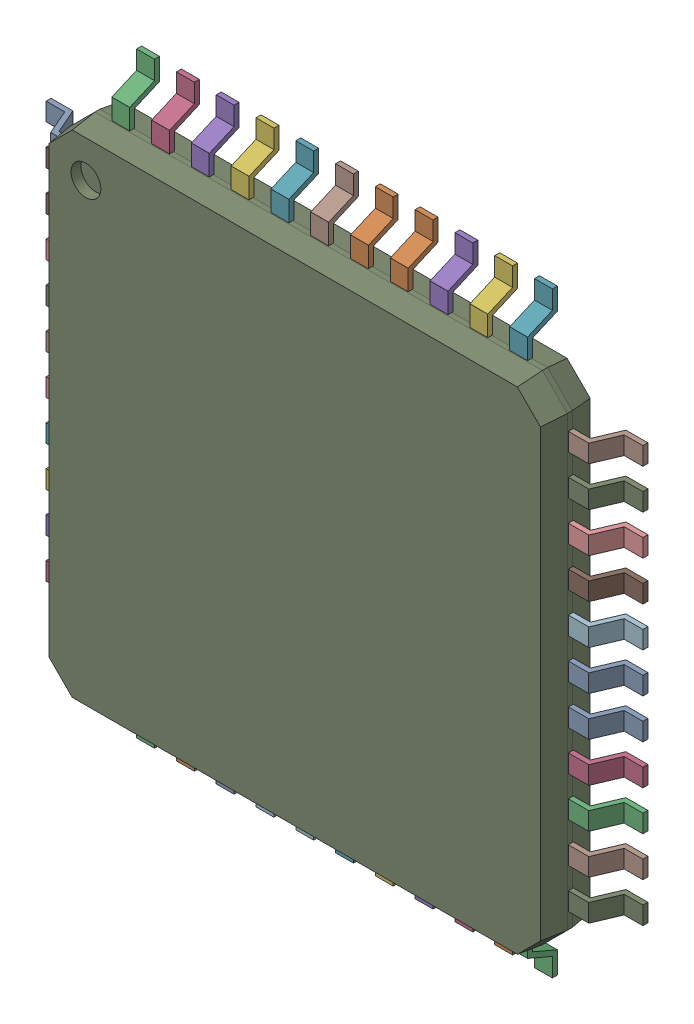
SolidWorks assembly DD2, configuration По умолчанию. Lengths in mm.
Overall size (12 12 1.1).
46 component instances, 45 part files, 0 mates.
Components (placement in the parent):
- User_Library-TQFP-44-1-1: User_Library-TQFP-44-1 [По умолчанию] at (28.4999 0.7811 0) x (0 -1 0) z (0 0 1) size (12 12 1.1)
  - User_Library-TQFP-44-1_pin001-1: User_Library-TQFP-44-1_pin001 [По умолчанию] at origin size (0.36 1 0.6)
  - User_Library-TQFP-44-1_pin021-1: User_Library-TQFP-44-1_pin021 [По умолчанию] at origin size (1 0.36 0.6)
  - User_Library-TQFP-44-1_pin022-1: User_Library-TQFP-44-1_pin022 [По умолчанию] at origin size (1 0.36 0.6)
  - User_Library-TQFP-44-1_pin020-1: User_Library-TQFP-44-1_pin020 [По умолчанию] at origin size (1 0.36 0.6)
  - User_Library-TQFP-44-1_pin019-1: User_Library-TQFP-44-1_pin019 [По умолчанию] at origin size (1 0.36 0.6)
  - User_Library-TQFP-44-1_pin018-1: User_Library-TQFP-44-1_pin018 [По умолчанию] at origin size (1 0.36 0.6)
  - User_Library-TQFP-44-1_pin017-1: User_Library-TQFP-44-1_pin017 [По умолчанию] at origin size (1 0.36 0.6)
  - User_Library-TQFP-44-1_pin024-1: User_Library-TQFP-44-1_pin024 [По умолчанию] at origin size (0.36 1 0.6)
  - User_Library-TQFP-44-1_pin023-1: User_Library-TQFP-44-1_pin023 [По умолчанию] at origin size (0.36 1 0.6)
  - User_Library-TQFP-44-1_pin007-1: User_Library-TQFP-44-1_pin007 [По умолчанию] at origin size (0.36 1 0.6)
  - User_Library-TQFP-44-1_pin003-1: User_Library-TQFP-44-1_pin003 [По умолчанию] at origin size (0.36 1 0.6)
  - User_Library-TQFP-44-1_pin015-1: User_Library-TQFP-44-1_pin015 [По умолчанию] at origin size (1 0.36 0.6)
  - User_Library-TQFP-44-1_pin014-1: User_Library-TQFP-44-1_pin014 [По умолчанию] at origin size (1 0.36 0.6)
  - User_Library-TQFP-44-1_pin013-1: User_Library-TQFP-44-1_pin013 [По умолчанию] at origin size (1 0.36 0.6)
  - User_Library-TQFP-44-1_pin012-1: User_Library-TQFP-44-1_pin012 [По умолчанию] at origin size (1 0.36 0.6)
  - User_Library-TQFP-44-1_pin011-1: User_Library-TQFP-44-1_pin011 [По умолчанию] at origin size (0.36 1 0.6)
  - User_Library-TQFP-44-1_pin010-1: User_Library-TQFP-44-1_pin010 [По умолчанию] at origin size (0.36 1 0.6)
  - User_Library-TQFP-44-1_pin009-1: User_Library-TQFP-44-1_pin009 [По умолчанию] at origin size (0.36 1 0.6)
  - User_Library-TQFP-44-1_pin008-1: User_Library-TQFP-44-1_pin008 [По умолчанию] at origin size (0.36 1 0.6)
  - User_Library-TQFP-44-1_pin006-1: User_Library-TQFP-44-1_pin006 [По умолчанию] at origin size (0.36 1 0.6)
  - User_Library-TQFP-44-1_pin005-1: User_Library-TQFP-44-1_pin005 [По умолчанию] at origin size (0.36 1 0.6)
  - User_Library-TQFP-44-1_pin004-1: User_Library-TQFP-44-1_pin004 [По умолчанию] at origin size (0.36 1 0.6)
  - User_Library-TQFP-44-1_pin002-1: User_Library-TQFP-44-1_pin002 [По умолчанию] at origin size (0.36 1 0.6)
  - User_Library-TQFP-44-1_pin016-1: User_Library-TQFP-44-1_pin016 [По умолчанию] at origin size (1 0.36 0.6)
  - User_Library-TQFP-44-1_pin027-1: User_Library-TQFP-44-1_pin027 [По умолчанию] at origin size (0.36 1 0.6)
  - User_Library-TQFP-44-1_pin037-1: User_Library-TQFP-44-1_pin037 [По умолчанию] at origin size (1 0.36 0.6)
  - User_Library-TQFP-44-1_pin025-1: User_Library-TQFP-44-1_pin025 [По умолчанию] at origin size (0.36 1 0.6)
  - User_Library-TQFP-44-1_pin026-1: User_Library-TQFP-44-1_pin026 [По умолчанию] at origin size (0.36 1 0.6)
  - User_Library-TQFP-44-1_pin036-1: User_Library-TQFP-44-1_pin036 [По умолчанию] at origin size (1 0.36 0.6)
  - User_Library-TQFP-44-1_pin035-1: User_Library-TQFP-44-1_pin035 [По умолчанию] at origin size (1 0.36 0.6)
  - User_Library-TQFP-44-1_pin034-1: User_Library-TQFP-44-1_pin034 [По умолчанию] at origin size (1 0.36 0.6)
  - User_Library-TQFP-44-1_pin033-1: User_Library-TQFP-44-1_pin033 [По умолчанию] at origin size (0.36 1 0.6)
  - User_Library-TQFP-44-1_pin032-1: User_Library-TQFP-44-1_pin032 [По умолчанию] at origin size (0.36 1 0.6)
  - User_Library-TQFP-44-1_pin031-1: User_Library-TQFP-44-1_pin031 [По умолчанию] at origin size (0.36 1 0.6)
  - User_Library-TQFP-44-1_pin030-1: User_Library-TQFP-44-1_pin030 [По умолчанию] at origin size (0.36 1 0.6)
  - User_Library-TQFP-44-1_pin029-1: User_Library-TQFP-44-1_pin029 [По умолчанию] at origin size (0.36 1 0.6)
  - User_Library-TQFP-44-1_pin028-1: User_Library-TQFP-44-1_pin028 [По умолчанию] at origin size (0.36 1 0.6)
  - User_Library-TQFP-44-1_pin038-1: User_Library-TQFP-44-1_pin038 [По умолчанию] at origin size (1 0.36 0.6)
  - User_Library-TQFP-44-1_pin044-1: User_Library-TQFP-44-1_pin044 [По умолчанию] at origin size (1 0.36 0.6)
  - User_Library-TQFP-44-1_pin043-1: User_Library-TQFP-44-1_pin043 [По умолчанию] at origin size (1 0.36 0.6)
  - User_Library-TQFP-44-1_pin042-1: User_Library-TQFP-44-1_pin042 [По умолчанию] at origin size (1 0.36 0.6)
  - User_Library-TQFP-44-1_pin041-1: User_Library-TQFP-44-1_pin041 [По умолчанию] at origin size (1 0.36 0.6)
  - User_Library-TQFP-44-1_pin040-1: User_Library-TQFP-44-1_pin040 [По умолчанию] at origin size (1 0.36 0.6)
  - User_Library-TQFP-44-1_pin039-1: User_Library-TQFP-44-1_pin039 [По умолчанию] at origin size (1 0.36 0.6)
  - User_Library-TQFP-44-1_Body-1: User_Library-TQFP-44-1_Body [По умолчанию] at origin size (10 10 1)
